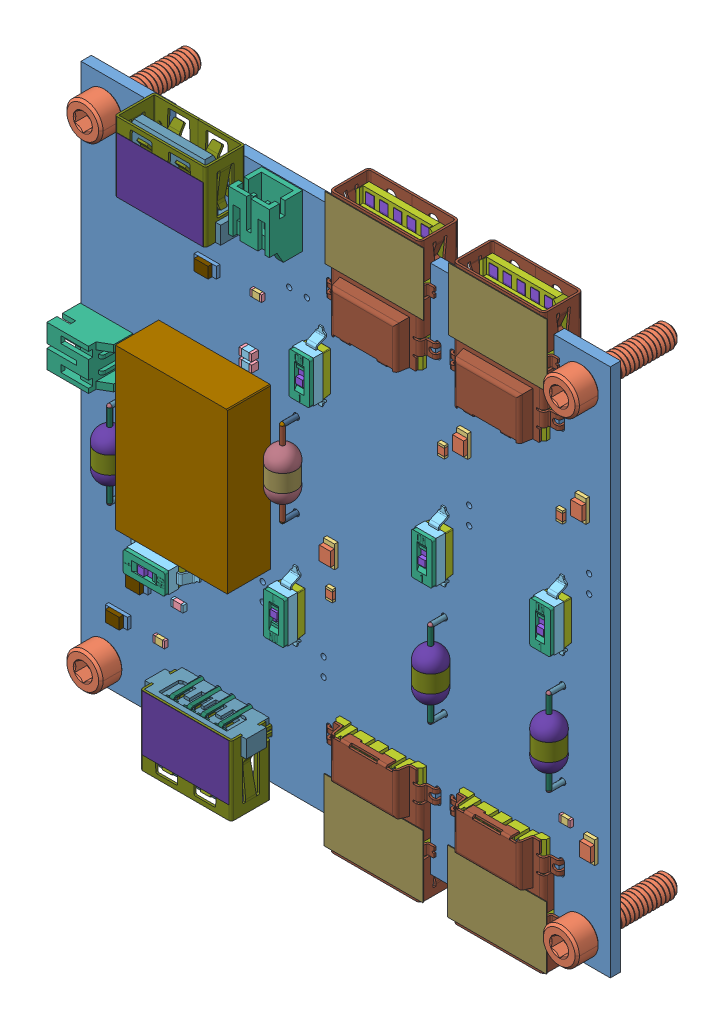
SolidWorks assembly SeniorDesign_PowerBoard_Rev1, configuration Default. Lengths in mm.
Overall size (76.32 82.41 18.82).
346 component instances, 45 part files, 0 mates.
Components (placement in the parent):
- SeniorDesign_PowerBoard_Rev1.step-1: SeniorDesign_PowerBoard_Rev1.step [Default] at origin size (76.32 82.41 18.82)
  - Board.step-1: Board.step [Default] at origin size (76.2 76.2 1.49)
    - Open CASCADE STEP translator 6.8 1.1.1.step-1: Open CASCADE STEP translator 6.8 1.1.1.step [Default] at (0 0 -1.4935) size (76.2 76.2 1.49)
      - Open CASCADE STEP translator 6.8 1.1.1.1.step-1: Open CASCADE STEP translator 6.8 1.1.1.1.step [Default] at origin size (76.2 76.2 1.49)
  - MNT4.step-1: MNT4.step [Default] at origin size (5.21 5.21 15.88)
    - 91251A128_BLACK-OXIDE_ALLOY_STEEL_SOCKET_HEAD_CAP_SCREW_RGB8421504.step-1: 91251A128_BLACK-OXIDE_ALLOY_STEEL_SOCKET_HEAD_CAP_SCREW_RGB8421504.step [Default] at (173.7359 54.4194 -12.319) x (1 0 0) z (0 0 -1) size (5.21 5.21 15.88)
  - MNT3.step-1: MNT3.step [Default] at origin size (5.21 5.21 15.88)
    - 91251A128_BLACK-OXIDE_ALLOY_STEEL_SOCKET_HEAD_CAP_SCREW_RGB8421504.step-1: 91251A128_BLACK-OXIDE_ALLOY_STEEL_SOCKET_HEAD_CAP_SCREW_RGB8421504.step [Default] at (105.1559 54.4194 -12.319) x (1 0 0) z (0 0 -1) size (5.21 5.21 15.88)
  - MNT2.step-1: MNT2.step [Default] at origin size (5.21 5.21 15.88)
    - 91251A128_BLACK-OXIDE_ALLOY_STEEL_SOCKET_HEAD_CAP_SCREW_RGB8421504.step-1: 91251A128_BLACK-OXIDE_ALLOY_STEEL_SOCKET_HEAD_CAP_SCREW_RGB8421504.step [Default] at (173.7359 122.9994 -12.319) x (1 0 0) z (0 0 -1) size (5.21 5.21 15.88)
  - MNT1.step-1: MNT1.step [Default] at origin size (5.21 5.21 15.88)
    - 91251A128_BLACK-OXIDE_ALLOY_STEEL_SOCKET_HEAD_CAP_SCREW_RGB8421504.step-1: 91251A128_BLACK-OXIDE_ALLOY_STEEL_SOCKET_HEAD_CAP_SCREW_RGB8421504.step [Default] at (105.1559 122.9994 -12.319) x (1 0 0) z (0 0 -1) size (5.21 5.21 15.88)
  - R1.step-1: R1.step [Default] at origin size (1.65 0.95 0.5)
    - 6174197136.step-1: 6174197136.step [Default] at (113.03 60.579 0) size (1.05 0.95 0.5)
      - Extruded.step-1: Extruded.step [Default] at origin size (1.05 0.95 0.5)
    - 6174196816.step-1: 6174196816.step [Default] at (112.355 60.579 0) size (0.3 0.95 0.5)
      - Extruded-0.step-1: Extruded-0.step [Default] at origin size (0.3 0.95 0.5)
    - 6174196816.step-2: 6174196816.step [Default] at (113.705 60.579 0) size (0.3 0.95 0.5)
      - Extruded-0.step-1: Extruded-0.step [Default] at origin size (0.3 0.95 0.5)
  - SW5.step-1: SW5.step [Default] at origin size (2.98 9.9 3.3)
    - 418121160801.step-1: 418121160801.step [Default] at (136.0171 106.2991 2.71) x (1 0 0) z (0 0 1) size (2.98 9.9 3.3)
      - base.step-1: base.step [Default] at origin size (2.98 9.9 2.75)
      - cap.step-1: cap.step [Default] at origin size (2.98 6 0.55)
      - insulator.step-1: insulator.step [Default] at (0 0 -1.4) size (2.98 5.9 1.25)
      - clip.step-1: clip.step [Default] at origin size (1.4 3.46 1)
      - clip.step-2: clip.step [Default] at origin size (1.4 3.46 1)
      - clip.step-3: clip.step [Default] at origin size (1.4 3.46 1)
      - clip.step-4: clip.step [Default] at origin size (1.4 3.46 1)
      - clip.step-5: clip.step [Default] at origin size (1.4 3.46 1)
      - clip.step-6: clip.step [Default] at origin size (1.4 3.46 1)
      - clip.step-7: clip.step [Default] at origin size (1.4 3.46 1)
      - clip.step-8: clip.step [Default] at origin size (1.4 3.46 1)
  - SW4.step-1: SW4.step [Default] at origin size (2.98 9.9 3.3)
    - 418121160801.step-1: 418121160801.step [Default] at (153.6507 92.6299 2.71) size (2.98 9.9 3.3)
      - base.step-1: base.step [Default] at origin size (2.98 9.9 2.75)
      - cap.step-1: cap.step [Default] at origin size (2.98 6 0.55)
      - insulator.step-1: insulator.step [Default] at (0 0 -1.4) size (2.98 5.9 1.25)
      - clip.step-1: clip.step [Default] at origin size (1.4 3.46 1)
      - clip.step-2: clip.step [Default] at origin size (1.4 3.46 1)
      - clip.step-3: clip.step [Default] at origin size (1.4 3.46 1)
      - clip.step-4: clip.step [Default] at origin size (1.4 3.46 1)
      - clip.step-5: clip.step [Default] at origin size (1.4 3.46 1)
      - clip.step-6: clip.step [Default] at origin size (1.4 3.46 1)
      - clip.step-7: clip.step [Default] at origin size (1.4 3.46 1)
      - clip.step-8: clip.step [Default] at origin size (1.4 3.46 1)
  - SW2.step-1: SW2.step [Default] at origin size (2.98 9.9 3.3)
    - 418121160801.step-1: 418121160801.step [Default] at (170.6881 92.5831 2.71) size (2.98 9.9 3.3)
      - base.step-1: base.step [Default] at origin size (2.98 9.9 2.75)
      - cap.step-1: cap.step [Default] at origin size (2.98 6 0.55)
      - insulator.step-1: insulator.step [Default] at (0 0 -1.4) size (2.98 5.9 1.25)
      - clip.step-1: clip.step [Default] at origin size (1.4 3.46 1)
      - clip.step-2: clip.step [Default] at origin size (1.4 3.46 1)
      - clip.step-3: clip.step [Default] at origin size (1.4 3.46 1)
      - clip.step-4: clip.step [Default] at origin size (1.4 3.46 1)
      - clip.step-5: clip.step [Default] at origin size (1.4 3.46 1)
      - clip.step-6: clip.step [Default] at origin size (1.4 3.46 1)
      - clip.step-7: clip.step [Default] at origin size (1.4 3.46 1)
      - clip.step-8: clip.step [Default] at origin size (1.4 3.46 1)
  - SW1.step-1: SW1.step [Default] at origin size (2.98 9.9 3.3)
    - 418121160801.step-1: 418121160801.step [Default] at (132.3339 74.5489 2.71) x (-1 0 0) z (0 0 1) size (2.98 9.9 3.3)
      - base.step-1: base.step [Default] at origin size (2.98 9.9 2.75)
      - cap.step-1: cap.step [Default] at origin size (2.98 6 0.55)
      - insulator.step-1: insulator.step [Default] at (0 0 -1.4) size (2.98 5.9 1.25)
      - clip.step-1: clip.step [Default] at origin size (1.4 3.46 1)
      - clip.step-2: clip.step [Default] at origin size (1.4 3.46 1)
      - clip.step-3: clip.step [Default] at origin size (1.4 3.46 1)
      - clip.step-4: clip.step [Default] at origin size (1.4 3.46 1)
      - clip.step-5: clip.step [Default] at origin size (1.4 3.46 1)
      - clip.step-6: clip.step [Default] at origin size (1.4 3.46 1)
      - clip.step-7: clip.step [Default] at origin size (1.4 3.46 1)
      - clip.step-8: clip.step [Default] at origin size (1.4 3.46 1)
  - F1.step-1: F1.step [Default] at origin size (3.94 12.64 5.94)
    - 6173972560.step-1: 6173972560.step [Default] at (132.3339 98.0751 1.97) x (0 1 0) z (0 0 1) size (0.64 0.64 0.64)
      - Sphere.step-1: Sphere.step [Default] at origin size (0.64 0.64 0.64)
    - 6173972560.step-2: 6173972560.step [Default] at (132.3337 86.0752 1.97) x (0 1 0) z (0 0 1) size (0.64 0.64 0.64)
      - Sphere.step-1: Sphere.step [Default] at origin size (0.64 0.64 0.64)
    - 6173972160.step-1: 6173972160.step [Default] at (132.3339 98.0751 -2) x (0 1 0) z (0 0 1) size (0.64 0.64 3.97)
      - Cylinder.step-1: Cylinder.step [Default] at origin size (0.64 0.64 3.97)
    - 6173972160.step-2: 6173972160.step [Default] at (132.3339 86.075 -2) x (0 1 0) z (0 0 1) size (0.64 0.64 3.97)
      - Cylinder.step-1: Cylinder.step [Default] at origin size (0.64 0.64 3.97)
    - 6173971760.step-1: 6173971760.step [Default] at (132.3341 95.6299 1.97) x (0 0 -1) z (0 1 0) size (0.64 0.64 2.44)
      - Cylinder-1.step-1: Cylinder-1.step [Default] at origin size (0.64 0.64 2.44)
    - 6173971760.step-2: 6173971760.step [Default] at (132.3339 86.075 1.97) x (0 0 -1) z (0 1 0) size (0.64 0.64 2.44)
      - Cylinder-1.step-1: Cylinder-1.step [Default] at origin size (0.64 0.64 2.44)
    - 6173971360.step-1: 6173971360.step [Default] at (132.3341 90.8249 1.97) x (0 0 -1) z (0 1 0) size (3.9 3.9 2.5)
      - Cylinder-2.step-1: Cylinder-2.step [Default] at origin size (3.9 3.9 2.5)
    - 6173971120.step-1: 6173971120.step [Default] at (132.3339 90.49 1.97) x (0 1 0) z (0 0 1) size (3.94 3.94 3.94)
      - Sphere-3.step-1: Sphere-3.step [Default] at origin size (3.94 3.94 3.94)
    - 6173971120.step-2: 6173971120.step [Default] at (132.3339 93.6601 1.97) x (0 1 0) z (0 0 1) size (3.94 3.94 3.94)
      - Sphere-3.step-1: Sphere-3.step [Default] at origin size (3.94 3.94 3.94)
  - SW3.step-1: SW3.step [Default] at origin size (9.9 2.98 3.3)
    - 418121160801.step-1: 418121160801.step [Default] at (113.6651 70.8659 2.71) x (0 -1 0) z (0 0 1) size (2.98 9.9 3.3)
      - base.step-1: base.step [Default] at origin size (2.98 9.9 2.75)
      - cap.step-1: cap.step [Default] at origin size (2.98 6 0.55)
      - insulator.step-1: insulator.step [Default] at (0 0 -1.4) size (2.98 5.9 1.25)
      - clip.step-1: clip.step [Default] at origin size (1.4 3.46 1)
      - clip.step-2: clip.step [Default] at origin size (1.4 3.46 1)
      - clip.step-3: clip.step [Default] at origin size (1.4 3.46 1)
      - clip.step-4: clip.step [Default] at origin size (1.4 3.46 1)
      - clip.step-5: clip.step [Default] at origin size (1.4 3.46 1)
      - clip.step-6: clip.step [Default] at origin size (1.4 3.46 1)
      - clip.step-7: clip.step [Default] at origin size (1.4 3.46 1)
      - clip.step-8: clip.step [Default] at origin size (1.4 3.46 1)
  - J1.step-1: J1.step [Default] at origin size (14.6 10 7.71)
    - 614104190121.step-1: 614104190121.step [Default] at (122.1739 57.9939 2.74) size (14.6 10 7.71)
      - 614104190121_Housing.step-1: 614104190121_Housing.step [Default] at origin size (14.6 9.6 5.86)
      - 614104190121_Pin.step-1: 614104190121_Pin.step [Default] at (3.5 -3.571 1.56) size (1.7 8.4 5.81)
      - 614104190121_Pin.step-2: 614104190121_Pin.step [Default] at (1 -3.571 1.56) size (1.7 8.4 5.81)
      - 614104190121_Pin.step-3: 614104190121_Pin.step [Default] at (-3.5 -3.571 1.56) size (1.7 8.4 5.81)
      - 614104190121_Pin.step-4: 614104190121_Pin.step [Default] at (-1 -3.571 1.56) size (1.7 8.4 5.81)
      - 614104190121_Shielding.step-1: 614104190121_Shielding.step [Default] at (0 -4.4 0.15) size (13.1 10 7.66)
      - 614104190121_Mylar.step-1: 614104190121_Mylar.step [Default] at (0 -3.4 3.01) size (12.5 8 0.05)
  - R3.step-1: R3.step [Default] at origin size (2.2 1.45 0.5)
    - 6173981440.step-1: 6173981440.step [Default] at (123.444 93.98 -1.9935) size (1.6 1.45 0.5)
      - Extruded-4.step-1: Extruded-4.step [Default] at origin size (1.6 1.45 0.5)
    - 6173981120.step-1: 6173981120.step [Default] at (124.394 93.98 -1.9935) size (0.3 1.45 0.5)
      - Extruded-5.step-1: Extruded-5.step [Default] at origin size (0.3 1.45 0.5)
    - 6173981120.step-2: 6173981120.step [Default] at (122.494 93.98 -1.9935) size (0.3 1.45 0.5)
      - Extruded-5.step-1: Extruded-5.step [Default] at origin size (0.3 1.45 0.5)
  - R8.step-1: R8.step [Default] at origin size (0.95 1.65 0.5)
    - 6174197936.step-1: 6174197936.step [Default] at (137.541 78.74 0) size (0.95 1.05 0.5)
      - Extruded-6.step-1: Extruded-6.step [Default] at origin size (0.95 1.05 0.5)
    - 6174197536.step-1: 6174197536.step [Default] at (137.541 78.065 0) size (0.95 0.3 0.5)
      - Extruded-7.step-1: Extruded-7.step [Default] at origin size (0.95 0.3 0.5)
    - 6174197536.step-2: 6174197536.step [Default] at (137.541 79.415 0) size (0.95 0.3 0.5)
      - Extruded-7.step-1: Extruded-7.step [Default] at origin size (0.95 0.3 0.5)
  - R7.step-1: R7.step [Default] at origin size (1.65 0.95 0.5)
    - 6174197136.step-1: 6174197136.step [Default] at (127 110.744 0) size (1.05 0.95 0.5)
      - Extruded.step-1: Extruded.step [Default] at origin size (1.05 0.95 0.5)
    - 6174196816.step-1: 6174196816.step [Default] at (126.325 110.744 0) size (0.3 0.95 0.5)
      - Extruded-0.step-1: Extruded-0.step [Default] at origin size (0.3 0.95 0.5)
    - 6174196816.step-2: 6174196816.step [Default] at (127.675 110.744 0) size (0.3 0.95 0.5)
      - Extruded-0.step-1: Extruded-0.step [Default] at origin size (0.3 0.95 0.5)
  - R6.step-1: R6.step [Default] at origin size (0.95 1.65 0.5)
    - 6174197936.step-1: 6174197936.step [Default] at (153.67 104.735 0) size (0.95 1.05 0.5)
      - Extruded-6.step-1: Extruded-6.step [Default] at origin size (0.95 1.05 0.5)
    - 6174197536.step-1: 6174197536.step [Default] at (153.67 105.41 0) size (0.95 0.3 0.5)
      - Extruded-7.step-1: Extruded-7.step [Default] at origin size (0.95 0.3 0.5)
    - 6174197536.step-2: 6174197536.step [Default] at (153.67 104.06 0) size (0.95 0.3 0.5)
      - Extruded-7.step-1: Extruded-7.step [Default] at origin size (0.95 0.3 0.5)
  - R4.step-1: R4.step [Default] at origin size (1.75 0.95 0.55)
    - 6173982160.step-1: 6173982160.step [Default] at (115.697 66.421 0) size (1.15 0.95 0.55)
      - Extruded-8.step-1: Extruded-8.step [Default] at origin size (1.15 0.95 0.55)
    - 6173981920.step-1: 6173981920.step [Default] at (114.972 66.421 0) size (0.3 0.95 0.55)
      - Extruded-9.step-1: Extruded-9.step [Default] at origin size (0.3 0.95 0.55)
    - 6173981920.step-2: 6173981920.step [Default] at (116.422 66.421 0) size (0.3 0.95 0.55)
      - Extruded-9.step-1: Extruded-9.step [Default] at origin size (0.3 0.95 0.55)
  - R2.step-1: R2.step [Default] at origin size (0.95 1.65 0.5)
    - 6174197936.step-1: 6174197936.step [Default] at (170.688 105.116 0) size (0.95 1.05 0.5)
      - Extruded-6.step-1: Extruded-6.step [Default] at origin size (0.95 1.05 0.5)
    - 6174197536.step-1: 6174197536.step [Default] at (170.688 105.791 0) size (0.95 0.3 0.5)
      - Extruded-7.step-1: Extruded-7.step [Default] at origin size (0.95 0.3 0.5)
    - 6174197536.step-2: 6174197536.step [Default] at (170.688 104.441 0) size (0.95 0.3 0.5)
      - Extruded-7.step-1: Extruded-7.step [Default] at origin size (0.95 0.3 0.5)
  - R5.step-1: R5.step [Default] at origin size (1.65 0.95 0.5)
    - 6174197136.step-1: 6174197136.step [Default] at (171.45 67.437 0) size (1.05 0.95 0.5)
      - Extruded.step-1: Extruded.step [Default] at origin size (1.05 0.95 0.5)
    - 6174196816.step-1: 6174196816.step [Default] at (170.775 67.437 0) size (0.3 0.95 0.5)
      - Extruded-0.step-1: Extruded-0.step [Default] at origin size (0.3 0.95 0.5)
    - 6174196816.step-2: 6174196816.step [Default] at (172.125 67.437 0) size (0.3 0.95 0.5)
      - Extruded-0.step-1: Extruded-0.step [Default] at origin size (0.3 0.95 0.5)
  - P2.step-1: P2.step [Default] at origin size (5.9 7.6 8.2)
    - S2B-PH-K-S.step-1: S2B-PH-K-S.step [Default] at (122.5518 117.7858 6) x (-1 0 0) z (0 1 0) size (5.9 8.2 7.6)
  - P1.step-1: P1.step [Default] at origin size (7.6 5.9 8.2)
    - S2B-PH-K-S.step-1: S2B-PH-K-S.step [Default] at (110.1792 85.9758 6) x (0 -1 0) z (-1 0 0) size (5.9 8.2 7.6)
  - J5.step-1: J5.step [Default] at origin size (14.6 10 7.71)
    - 614104190121.step-1: 614104190121.step [Default] at (118.4911 118.9171 2.74) x (-1 0 0) z (0 0 1) size (14.6 10 7.71)
      - 614104190121_Housing.step-1: 614104190121_Housing.step [Default] at origin size (14.6 9.6 5.86)
      - 614104190121_Pin.step-1: 614104190121_Pin.step [Default] at (3.5 -3.571 1.56) size (1.7 8.4 5.81)
      - 614104190121_Pin.step-2: 614104190121_Pin.step [Default] at (1 -3.571 1.56) size (1.7 8.4 5.81)
      - 614104190121_Pin.step-3: 614104190121_Pin.step [Default] at (-3.5 -3.571 1.56) size (1.7 8.4 5.81)
      - 614104190121_Pin.step-4: 614104190121_Pin.step [Default] at (-1 -3.571 1.56) size (1.7 8.4 5.81)
      - 614104190121_Shielding.step-1: 614104190121_Shielding.step [Default] at (0 -4.4 0.15) size (13.1 10 7.66)
      - 614104190121_Mylar.step-1: 614104190121_Mylar.step [Default] at (0 -3.4 3.01) size (12.5 8 0.05)
  - J6.step-1: J6.step [Default] at origin size (16 16.37 7.4)
    - 692121330100.step-1: 692121330100.step [Default] at (144.907 59.138 -1.71) x (0 -1 0) z (0 0 1) size (16.37 16 7.4)
      - 692121330100_Housing.step-1: 692121330100_Housing.step [Default] at origin size (16 12.5 7.1)
      - 692121330100_Pin3.step-1: 692121330100_Pin3.step [Default] at (-1.13 -4 0.225) x (-1 0 0) z (0 0 1) size (13.17 1.2 3.8)
      - 692121330100_Pin3.step-2: 692121330100_Pin3.step [Default] at (-1.13 4 0.225) x (-1 0 0) z (0 0 1) size (13.17 1.2 3.8)
      - 692121330100_Pin3.step-3: 692121330100_Pin3.step [Default] at (-1.13 2 0.225) x (-1 0 0) z (0 0 1) size (13.17 1.2 3.8)
      - 692121330100_Pin3.step-4: 692121330100_Pin3.step [Default] at (-1.13 0 0.225) x (-1 0 0) z (0 0 1) size (13.17 1.2 3.8)
      - 692121330100_Pin3.step-5: 692121330100_Pin3.step [Default] at (-1.13 -2 0.225) x (-1 0 0) z (0 0 1) size (13.17 1.2 3.8)
      - 692121330100_Pin2.step-1: 692121330100_Pin2.step [Default] at (0.6494 1 1.6597) x (-1 0 0) z (0 0 1) size (12.15 1.61 5.43)
      - 692121330100_Pin2.step-2: 692121330100_Pin2.step [Default] at (0.6494 -1 1.6597) x (-1 0 0) z (0 0 1) size (12.15 1.61 5.43)
      - 692121330100_Pin1.step-1: 692121330100_Pin1.step [Default] at (0.65 3.5 1.6597) x (-1 0 0) z (0 0 1) size (12.15 1.6 5.42)
      - 692121330100_Pin1.step-2: 692121330100_Pin1.step [Default] at (0.65 -3.5 1.6597) x (-1 0 0) z (0 0 1) size (12.15 1.6 5.42)
      - 692121330100_Shielding.step-1: 692121330100_Shielding.step [Default] at (3.385 0 0.15) x (0 -1 0) z (0 0 1) size (16 16.37 7.4)
      - 692121330100_Mylar.step-1: 692121330100_Mylar.step [Default] at (6.69 -0.05 3.11) x (-1 0 0) z (0 -1 0) size (9 0.1 14.2)
  - J4.step-1: J4.step [Default] at origin size (16 16.37 7.4)
    - 692121330100.step-1: 692121330100.step [Default] at (144.907 118.408 -1.71) x (0 1 0) z (0 0 1) size (16.37 16 7.4)
      - 692121330100_Housing.step-1: 692121330100_Housing.step [Default] at origin size (16 12.5 7.1)
      - 692121330100_Pin3.step-1: 692121330100_Pin3.step [Default] at (-1.13 -4 0.225) x (-1 0 0) z (0 0 1) size (13.17 1.2 3.8)
      - 692121330100_Pin3.step-2: 692121330100_Pin3.step [Default] at (-1.13 4 0.225) x (-1 0 0) z (0 0 1) size (13.17 1.2 3.8)
      - 692121330100_Pin3.step-3: 692121330100_Pin3.step [Default] at (-1.13 2 0.225) x (-1 0 0) z (0 0 1) size (13.17 1.2 3.8)
      - 692121330100_Pin3.step-4: 692121330100_Pin3.step [Default] at (-1.13 0 0.225) x (-1 0 0) z (0 0 1) size (13.17 1.2 3.8)
      - 692121330100_Pin3.step-5: 692121330100_Pin3.step [Default] at (-1.13 -2 0.225) x (-1 0 0) z (0 0 1) size (13.17 1.2 3.8)
      - 692121330100_Pin2.step-1: 692121330100_Pin2.step [Default] at (0.6494 1 1.6597) x (-1 0 0) z (0 0 1) size (12.15 1.61 5.43)
      - 692121330100_Pin2.step-2: 692121330100_Pin2.step [Default] at (0.6494 -1 1.6597) x (-1 0 0) z (0 0 1) size (12.15 1.61 5.43)
      - 692121330100_Pin1.step-1: 692121330100_Pin1.step [Default] at (0.65 3.5 1.6597) x (-1 0 0) z (0 0 1) size (12.15 1.6 5.42)
      - 692121330100_Pin1.step-2: 692121330100_Pin1.step [Default] at (0.65 -3.5 1.6597) x (-1 0 0) z (0 0 1) size (12.15 1.6 5.42)
      - 692121330100_Shielding.step-1: 692121330100_Shielding.step [Default] at (3.385 0 0.15) x (0 -1 0) z (0 0 1) size (16 16.37 7.4)
      - 692121330100_Mylar.step-1: 692121330100_Mylar.step [Default] at (6.69 -0.05 3.11) x (-1 0 0) z (0 -1 0) size (9 0.1 14.2)
  - J3.step-1: J3.step [Default] at origin size (16 16.37 7.4)
    - 692121330100.step-1: 692121330100.step [Default] at (162.687 59.138 -1.71) x (0 -1 0) z (0 0 1) size (16.37 16 7.4)
      - 692121330100_Housing.step-1: 692121330100_Housing.step [Default] at origin size (16 12.5 7.1)
      - 692121330100_Pin3.step-1: 692121330100_Pin3.step [Default] at (-1.13 -4 0.225) x (-1 0 0) z (0 0 1) size (13.17 1.2 3.8)
      - 692121330100_Pin3.step-2: 692121330100_Pin3.step [Default] at (-1.13 4 0.225) x (-1 0 0) z (0 0 1) size (13.17 1.2 3.8)
      - 692121330100_Pin3.step-3: 692121330100_Pin3.step [Default] at (-1.13 2 0.225) x (-1 0 0) z (0 0 1) size (13.17 1.2 3.8)
      - 692121330100_Pin3.step-4: 692121330100_Pin3.step [Default] at (-1.13 0 0.225) x (-1 0 0) z (0 0 1) size (13.17 1.2 3.8)
      - 692121330100_Pin3.step-5: 692121330100_Pin3.step [Default] at (-1.13 -2 0.225) x (-1 0 0) z (0 0 1) size (13.17 1.2 3.8)
      - 692121330100_Pin2.step-1: 692121330100_Pin2.step [Default] at (0.6494 1 1.6597) x (-1 0 0) z (0 0 1) size (12.15 1.61 5.43)
      - 692121330100_Pin2.step-2: 692121330100_Pin2.step [Default] at (0.6494 -1 1.6597) x (-1 0 0) z (0 0 1) size (12.15 1.61 5.43)
      - 692121330100_Pin1.step-1: 692121330100_Pin1.step [Default] at (0.65 3.5 1.6597) x (-1 0 0) z (0 0 1) size (12.15 1.6 5.42)
      - 692121330100_Pin1.step-2: 692121330100_Pin1.step [Default] at (0.65 -3.5 1.6597) x (-1 0 0) z (0 0 1) size (12.15 1.6 5.42)
      - 692121330100_Shielding.step-1: 692121330100_Shielding.step [Default] at (3.385 0 0.15) x (0 -1 0) z (0 0 1) size (16 16.37 7.4)
      - 692121330100_Mylar.step-1: 692121330100_Mylar.step [Default] at (6.69 -0.05 3.11) x (-1 0 0) z (0 -1 0) size (9 0.1 14.2)
  - J2.step-1: J2.step [Default] at origin size (16 16.37 7.4)
    - 692121330100.step-1: 692121330100.step [Default] at (162.687 118.408 -1.71) x (0 1 0) z (0 0 1) size (16.37 16 7.4)
      - 692121330100_Housing.step-1: 692121330100_Housing.step [Default] at origin size (16 12.5 7.1)
      - 692121330100_Pin3.step-1: 692121330100_Pin3.step [Default] at (-1.13 -4 0.225) x (-1 0 0) z (0 0 1) size (13.17 1.2 3.8)
      - 692121330100_Pin3.step-2: 692121330100_Pin3.step [Default] at (-1.13 4 0.225) x (-1 0 0) z (0 0 1) size (13.17 1.2 3.8)
      - 692121330100_Pin3.step-3: 692121330100_Pin3.step [Default] at (-1.13 2 0.225) x (-1 0 0) z (0 0 1) size (13.17 1.2 3.8)
      - 692121330100_Pin3.step-4: 692121330100_Pin3.step [Default] at (-1.13 0 0.225) x (-1 0 0) z (0 0 1) size (13.17 1.2 3.8)
      - 692121330100_Pin3.step-5: 692121330100_Pin3.step [Default] at (-1.13 -2 0.225) x (-1 0 0) z (0 0 1) size (13.17 1.2 3.8)
      - 692121330100_Pin2.step-1: 692121330100_Pin2.step [Default] at (0.6494 1 1.6597) x (-1 0 0) z (0 0 1) size (12.15 1.61 5.43)
      - 692121330100_Pin2.step-2: 692121330100_Pin2.step [Default] at (0.6494 -1 1.6597) x (-1 0 0) z (0 0 1) size (12.15 1.61 5.43)
      - 692121330100_Pin1.step-1: 692121330100_Pin1.step [Default] at (0.65 3.5 1.6597) x (-1 0 0) z (0 0 1) size (12.15 1.6 5.42)
      - 692121330100_Pin1.step-2: 692121330100_Pin1.step [Default] at (0.65 -3.5 1.6597) x (-1 0 0) z (0 0 1) size (12.15 1.6 5.42)
      - 692121330100_Shielding.step-1: 692121330100_Shielding.step [Default] at (3.385 0 0.15) x (0 -1 0) z (0 0 1) size (16 16.37 7.4)
      - 692121330100_Mylar.step-1: 692121330100_Mylar.step [Default] at (6.69 -0.05 3.11) x (-1 0 0) z (0 -1 0) size (9 0.1 14.2)
  - F4.step-1: F4.step [Default] at origin size (3.94 12.64 5.94)
    - 6173978080.step-1: 6173978080.step [Default] at (153.6507 71.724 1.97) x (0 -1 0) z (0 0 1) size (0.64 0.64 0.64)
      - Sphere-10.step-1: Sphere-10.step [Default] at origin size (0.64 0.64 0.64)
    - 6173978080.step-2: 6173978080.step [Default] at (153.6508 83.7238 1.97) x (0 -1 0) z (0 0 1) size (0.64 0.64 0.64)
      - Sphere-10.step-1: Sphere-10.step [Default] at origin size (0.64 0.64 0.64)
    - 6173977520.step-1: 6173977520.step [Default] at (153.6507 71.7239 -2) x (0 -1 0) z (0 0 1) size (0.64 0.64 3.97)
      - Cylinder-11.step-1: Cylinder-11.step [Default] at origin size (0.64 0.64 3.97)
    - 6173977520.step-2: 6173977520.step [Default] at (153.6507 83.724 -2) x (0 -1 0) z (0 0 1) size (0.64 0.64 3.97)
      - Cylinder-11.step-1: Cylinder-11.step [Default] at origin size (0.64 0.64 3.97)
    - 6173976880.step-1: 6173976880.step [Default] at (153.6505 74.1691 1.97) x (0 0 -1) z (0 -1 0) size (0.64 0.64 2.44)
      - Cylinder-12.step-1: Cylinder-12.step [Default] at origin size (0.64 0.64 2.44)
    - 6173976880.step-2: 6173976880.step [Default] at (153.6507 83.724 1.97) x (0 0 -1) z (0 -1 0) size (0.64 0.64 2.44)
      - Cylinder-12.step-1: Cylinder-12.step [Default] at origin size (0.64 0.64 2.44)
    - 6173976320.step-1: 6173976320.step [Default] at (153.6505 78.9741 1.97) x (0 0 -1) z (0 -1 0) size (3.9 3.9 2.5)
      - Cylinder-13.step-1: Cylinder-13.step [Default] at origin size (3.9 3.9 2.5)
    - 6173975840.step-1: 6173975840.step [Default] at (153.6507 79.309 1.97) x (0 -1 0) z (0 0 1) size (3.94 3.94 3.94)
      - Sphere-14.step-1: Sphere-14.step [Default] at origin size (3.94 3.94 3.94)
    - 6173975840.step-2: 6173975840.step [Default] at (153.6507 76.1389 1.97) x (0 -1 0) z (0 0 1) size (3.94 3.94 3.94)
      - Sphere-14.step-1: Sphere-14.step [Default] at origin size (3.94 3.94 3.94)
  - F3.step-1: F3.step [Default] at origin size (3.94 12.64 5.94)
    - 6173978080.step-1: 6173978080.step [Default] at (107.4421 75.9149 1.97) x (0 -1 0) z (0 0 1) size (0.64 0.64 0.64)
      - Sphere-10.step-1: Sphere-10.step [Default] at origin size (0.64 0.64 0.64)
    - 6173978080.step-2: 6173978080.step [Default] at (107.4423 87.9148 1.97) x (0 -1 0) z (0 0 1) size (0.64 0.64 0.64)
      - Sphere-10.step-1: Sphere-10.step [Default] at origin size (0.64 0.64 0.64)
    - 6173977520.step-1: 6173977520.step [Default] at (107.4421 75.9149 -2) x (0 -1 0) z (0 0 1) size (0.64 0.64 3.97)
      - Cylinder-11.step-1: Cylinder-11.step [Default] at origin size (0.64 0.64 3.97)
    - 6173977520.step-2: 6173977520.step [Default] at (107.4421 87.915 -2) x (0 -1 0) z (0 0 1) size (0.64 0.64 3.97)
      - Cylinder-11.step-1: Cylinder-11.step [Default] at origin size (0.64 0.64 3.97)
    - 6173976880.step-1: 6173976880.step [Default] at (107.4419 78.3601 1.97) x (0 0 -1) z (0 -1 0) size (0.64 0.64 2.44)
      - Cylinder-12.step-1: Cylinder-12.step [Default] at origin size (0.64 0.64 2.44)
    - 6173976880.step-2: 6173976880.step [Default] at (107.4421 87.915 1.97) x (0 0 -1) z (0 -1 0) size (0.64 0.64 2.44)
      - Cylinder-12.step-1: Cylinder-12.step [Default] at origin size (0.64 0.64 2.44)
    - 6173976320.step-1: 6173976320.step [Default] at (107.4419 83.1651 1.97) x (0 0 -1) z (0 -1 0) size (3.9 3.9 2.5)
      - Cylinder-13.step-1: Cylinder-13.step [Default] at origin size (3.9 3.9 2.5)
    - 6173975840.step-1: 6173975840.step [Default] at (107.4421 83.5 1.97) x (0 -1 0) z (0 0 1) size (3.94 3.94 3.94)
      - Sphere-14.step-1: Sphere-14.step [Default] at origin size (3.94 3.94 3.94)
    - 6173975840.step-2: 6173975840.step [Default] at (107.4421 80.3299 1.97) x (0 -1 0) z (0 0 1) size (3.94 3.94 3.94)
      - Sphere-14.step-1: Sphere-14.step [Default] at origin size (3.94 3.94 3.94)
  - F2.step-1: F2.step [Default] at origin size (3.94 12.64 5.94)
    - 6173978080.step-1: 6173978080.step [Default] at (170.6881 71.724 1.97) x (0 -1 0) z (0 0 1) size (0.64 0.64 0.64)
      - Sphere-10.step-1: Sphere-10.step [Default] at origin size (0.64 0.64 0.64)
    - 6173978080.step-2: 6173978080.step [Default] at (170.6883 83.7238 1.97) x (0 -1 0) z (0 0 1) size (0.64 0.64 0.64)
      - Sphere-10.step-1: Sphere-10.step [Default] at origin size (0.64 0.64 0.64)
    - 6173977520.step-1: 6173977520.step [Default] at (170.6881 71.7239 -2) x (0 -1 0) z (0 0 1) size (0.64 0.64 3.97)
      - Cylinder-11.step-1: Cylinder-11.step [Default] at origin size (0.64 0.64 3.97)
    - 6173977520.step-2: 6173977520.step [Default] at (170.6881 83.724 -2) x (0 -1 0) z (0 0 1) size (0.64 0.64 3.97)
      - Cylinder-11.step-1: Cylinder-11.step [Default] at origin size (0.64 0.64 3.97)
    - 6173976880.step-1: 6173976880.step [Default] at (170.6879 74.1691 1.97) x (0 0 -1) z (0 -1 0) size (0.64 0.64 2.44)
      - Cylinder-12.step-1: Cylinder-12.step [Default] at origin size (0.64 0.64 2.44)
    - 6173976880.step-2: 6173976880.step [Default] at (170.6881 83.724 1.97) x (0 0 -1) z (0 -1 0) size (0.64 0.64 2.44)
      - Cylinder-12.step-1: Cylinder-12.step [Default] at origin size (0.64 0.64 2.44)
    - 6173976320.step-1: 6173976320.step [Default] at (170.6879 78.9741 1.97) x (0 0 -1) z (0 -1 0) size (3.9 3.9 2.5)
      - Cylinder-13.step-1: Cylinder-13.step [Default] at origin size (3.9 3.9 2.5)
    - 6173975840.step-1: 6173975840.step [Default] at (170.6881 79.309 1.97) x (0 -1 0) z (0 0 1) size (3.94 3.94 3.94)
      - Sphere-14.step-1: Sphere-14.step [Default] at origin size (3.94 3.94 3.94)
    - 6173975840.step-2: 6173975840.step [Default] at (170.6881 76.1389 1.97) x (0 -1 0) z (0 0 1) size (3.94 3.94 3.94)
      - Sphere-14.step-1: Sphere-14.step [Default] at origin size (3.94 3.94 3.94)
  - D6.step-1: D6.step [Default] at origin size (3.2 1.6 1.1)
    - 6173970240.step-1: 6173970240.step [Default] at (119.733 110.744 0.5) size (2 1.6 0.6)
      - Extruded-15.step-1: Extruded-15.step [Default] at origin size (2 1.6 0.6)
    - 6173970000.step-1: 6173970000.step [Default] at (119.733 110.744 0) size (3.2 1.6 0.5)
      - Extruded-16.step-1: Extruded-16.step [Default] at origin size (3.2 1.6 0.5)
  - D7.step-1: D7.step [Default] at origin size (1.6 3.2 1.1)
    - 6173970720.step-1: 6173970720.step [Default] at (137.541 83.82 0.5) size (1.6 2 0.6)
      - Extruded-17.step-1: Extruded-17.step [Default] at origin size (1.6 2 0.6)
    - 6173970480.step-1: 6173970480.step [Default] at (137.541 83.82 0) size (1.6 3.2 0.5)
      - Extruded-18.step-1: Extruded-18.step [Default] at origin size (1.6 3.2 0.5)
  - D5.step-1: D5.step [Default] at origin size (1.6 3.2 1.1)
    - 6173970720.step-1: 6173970720.step [Default] at (156.718 107.16 0.5) size (1.6 2 0.6)
      - Extruded-17.step-1: Extruded-17.step [Default] at origin size (1.6 2 0.6)
    - 6173970480.step-1: 6173970480.step [Default] at (156.718 107.16 0) size (1.6 3.2 0.5)
      - Extruded-18.step-1: Extruded-18.step [Default] at origin size (1.6 3.2 0.5)
  - D3.step-1: D3.step [Default] at origin size (1.6 3.2 1.1)
    - 6173970720.step-1: 6173970720.step [Default] at (175.006 65.659 0.5) size (1.6 2 0.6)
      - Extruded-17.step-1: Extruded-17.step [Default] at origin size (1.6 2 0.6)
    - 6173970480.step-1: 6173970480.step [Default] at (175.006 65.659 0) size (1.6 3.2 0.5)
      - Extruded-18.step-1: Extruded-18.step [Default] at origin size (1.6 3.2 0.5)
  - D2.step-1: D2.step [Default] at origin size (1.6 3.2 1.1)
    - 6173970720.step-1: 6173970720.step [Default] at (173.736 107.569 0.5) size (1.6 2 0.6)
      - Extruded-17.step-1: Extruded-17.step [Default] at origin size (1.6 2 0.6)
    - 6173970480.step-1: 6173970480.step [Default] at (173.736 107.569 0) size (1.6 3.2 0.5)
      - Extruded-18.step-1: Extruded-18.step [Default] at origin size (1.6 3.2 0.5)
  - D1.step-1: D1.step [Default] at origin size (3.2 1.6 1.1)
    - 6173970240.step-1: 6173970240.step [Default] at (106.934 60.579 0.5) size (2 1.6 0.6)
      - Extruded-15.step-1: Extruded-15.step [Default] at origin size (2 1.6 0.6)
    - 6173970000.step-1: 6173970000.step [Default] at (106.934 60.579 0) size (3.2 1.6 0.5)
      - Extruded-16.step-1: Extruded-16.step [Default] at origin size (3.2 1.6 0.5)
  - D4.step-1: D4.step [Default] at origin size (3.2 1.6 1.1)
    - 6173970240.step-1: 6173970240.step [Default] at (109.855 66.421 0.5) size (2 1.6 0.6)
      - Extruded-15.step-1: Extruded-15.step [Default] at origin size (2 1.6 0.6)
    - 6173970000.step-1: 6173970000.step [Default] at (109.855 66.421 0) size (3.2 1.6 0.5)
      - Extruded-16.step-1: Extruded-16.step [Default] at origin size (3.2 1.6 0.5)
  - C1.step-1: C1.step [Default] at origin size (1.8 1 1)
    - 6173967840.step-1: 6173967840.step [Default] at (125.274 103.124 0) size (0.38 1 1)
      - Extruded-19.step-1: Extruded-19.step [Default] at origin size (0.38 1 1)
    - 6173967840.step-2: 6173967840.step [Default] at (126.694 103.124 0) size (0.38 1 1)
      - Extruded-19.step-1: Extruded-19.step [Default] at origin size (0.38 1 1)
    - 6173967440.step-1: 6173967440.step [Default] at (125.984 103.124 0) size (1.04 1 1)
      - Extruded-20.step-1: Extruded-20.step [Default] at origin size (1.04 1 1)
  - C2.step-1: C2.step [Default] at origin size (1.8 1 1)
    - 6173967840.step-1: 6173967840.step [Default] at (125.274 101.727 0) size (0.38 1 1)
      - Extruded-19.step-1: Extruded-19.step [Default] at origin size (0.38 1 1)
    - 6173967840.step-2: 6173967840.step [Default] at (126.694 101.727 0) size (0.38 1 1)
      - Extruded-19.step-1: Extruded-19.step [Default] at origin size (0.38 1 1)
    - 6173967440.step-1: 6173967440.step [Default] at (125.984 101.727 0) size (1.04 1 1)
      - Extruded-20.step-1: Extruded-20.step [Default] at origin size (1.04 1 1)
  - C3.step-1: C3.step [Default] at origin size (3.4 1.8 1.8)
    - 6157080976.step-1: 6157080976.step [Default] at (123.063 75.057 0) x (1 0 0) z (0 0 1) size (3.4 1.8 1.8)
      - Terminal.step-1: Terminal.step [Default] at (-1.7 -0.9 0) size (3.4 1.8 1.8)
        - Open_CASCADE_STEP_translator_6.8_8.1.1.step-1: Open_CASCADE_STEP_translator_6.8_8.1.1.step [Default] at origin size (0.3 1.8 1.8)
        - Open_CASCADE_STEP_translator_6.8_8.1.2.step-1: Open_CASCADE_STEP_translator_6.8_8.1.2.step [Default] at origin size (0.3 1.8 1.8)
      - Mid_Body.step-1: Mid_Body.step [Default] at (-1.7 -0.9 0) size (2.8 1.8 1.8)
        - Open_CASCADE_STEP_translator_6.8_8.2.1.step-1: Open_CASCADE_STEP_translator_6.8_8.2.1.step [Default] at origin size (2.8 1.8 1.8)
  - U1.step-1: U1.step [Default] at origin size (16.13 22.99 6.25)
    - 6173654480.step-1: 6173654480.step [Default] at (120.8405 88.9635 0.254) size (16.13 22.99 6.25)
      - Extruded-21.step-1: Extruded-21.step [Default] at origin size (16.13 22.99 6.25)
